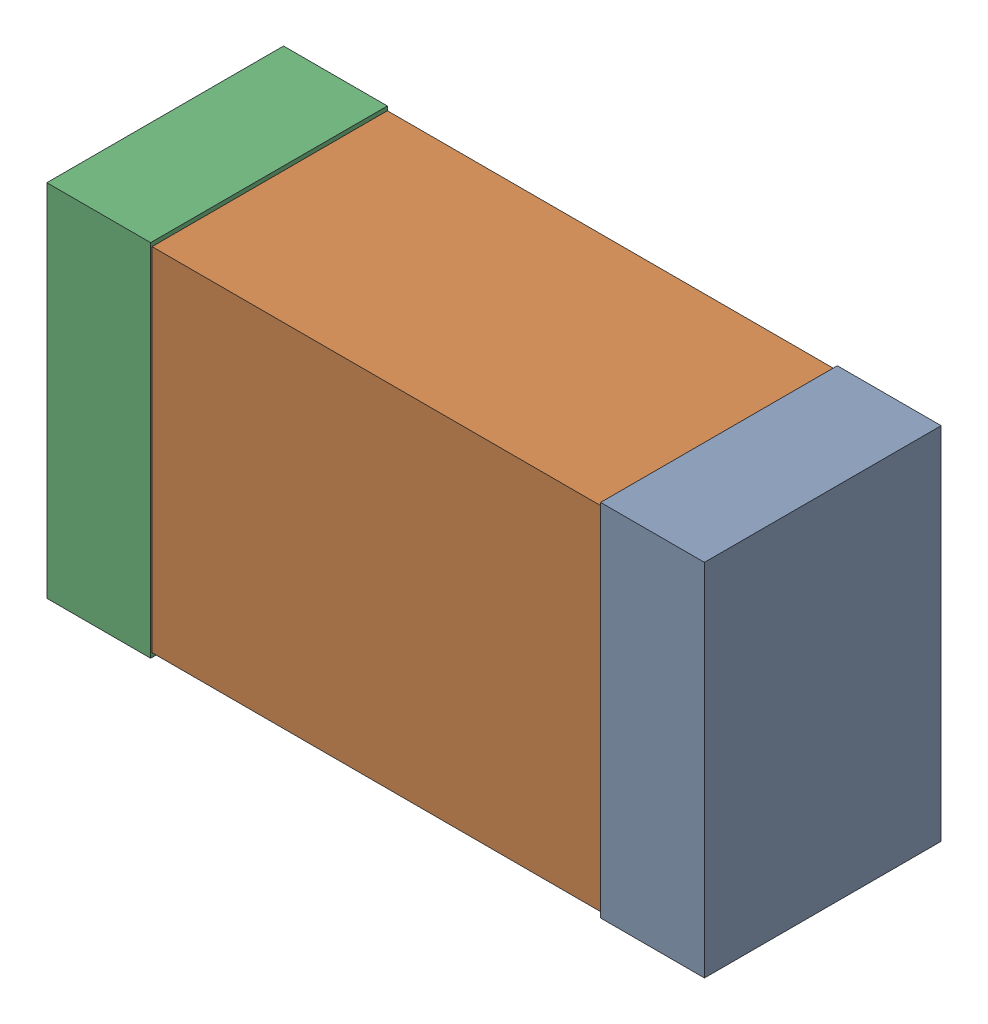
SolidWorks assembly CSSKanaloa_v2.0.0_Power_1, configuration Default. Lengths in mm.
Overall size (2.38 1.3 0.85).
6 component instances, 2 part files, 0 mates.
Components (placement in the parent):
- 352877648-1: 352877648 [Default] at (140.1516 56.0125 0) size (0.38 1.3 0.85)
  - Extruded_14-1: Extruded_14 [Default] at origin size (0.38 1.3 0.85)
- 352877392-1: 352877392 [Default] at (139.1516 56.0125 0) size (2.2 1.27 0.85)
  - Extruded_15-1: Extruded_15 [Default] at origin size (2.2 1.27 0.85)
- 352877648-2: 352877648 [Default] at (138.1516 56.0125 0) size (0.38 1.3 0.85)
  - Extruded_14-1: Extruded_14 [Default] at origin size (0.38 1.3 0.85)
